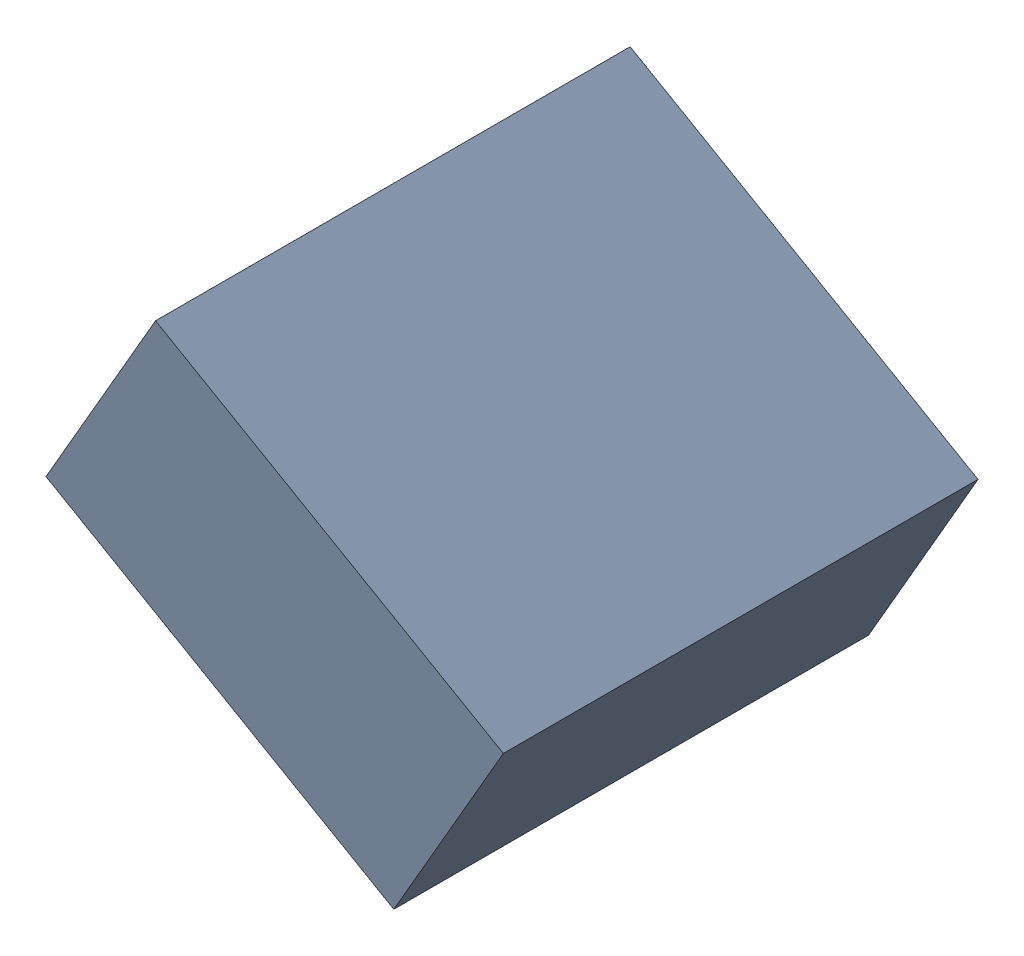
SolidWorks assembly C31_TDA6, configuration Standard. Lengths in mm.
Overall size (1.25 1.07 1.3).
2 component instances, 1 part files, 0 mates.
Components (placement in the parent):
- 885543056-1: 885543056 [Standard] at (-51.8712 31.5889 0) size (1.25 1.07 1.3)
  - Extruded_23-1: Extruded_23 [Standard] at origin size (1.25 1.07 1.3)
